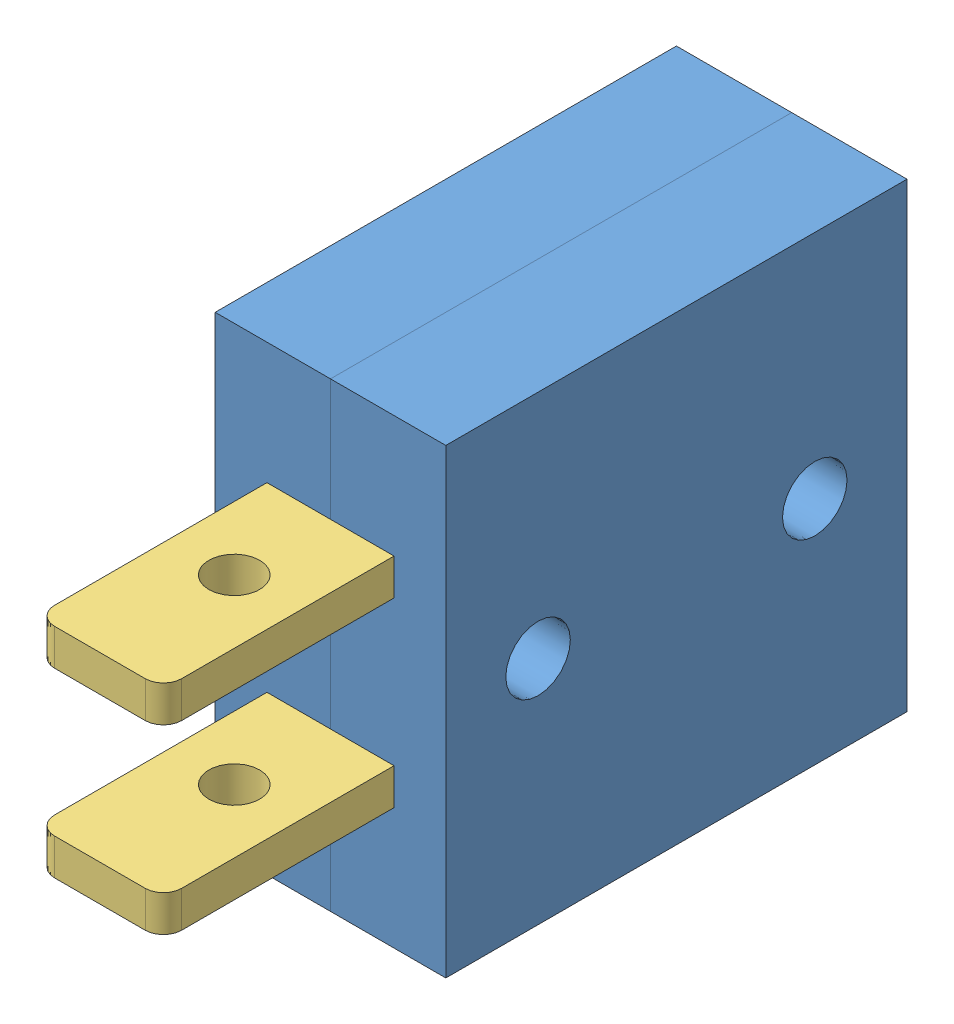
SolidWorks assembly ft-pwr-switch, configuration Default. Lengths in mm.
Overall size (6.35 12.88 19.05).
5 component instances, 3 part files, 0 mates.
Components (placement in the parent):
- Copy of PART A^ft-pwr-switch-1: Copy of PART A^ft-pwr-switch [Default] at origin size (3.18 12.7 12.7) (virtual)
- Copy of PART A^ft-pwr-switch-2: Copy of PART A^ft-pwr-switch [Default] x (-1 0 0) z (0 0 -1) size (3.18 12.7 12.7) (virtual)
- Copy of socket head cap screw_ai_HX-SHCS 0.086-56x0.375x0.375-S^ft-pwr-switch-1: Copy of socket head cap screw_ai_HX-SHCS 0.086-56x0.375x0.375-S^ft-pwr-switch [Default] at (0 -6.5344 0) x (0 1 0) z (0 0 1) size (11.71 3.56 3.56) (virtual)
- Copy of TERMINAL^ft-pwr-switch-1: Copy of TERMINAL^ft-pwr-switch [Default] at (0 2 3.7) x (0 0 -1) z (0 1 0) size (18 3.5 1) (virtual)
- Copy of TERMINAL^ft-pwr-switch-2: Copy of TERMINAL^ft-pwr-switch [Default] at (0 -3 3.7) x (0 0 -1) z (0 1 0) size (18 3.5 1) (virtual)
